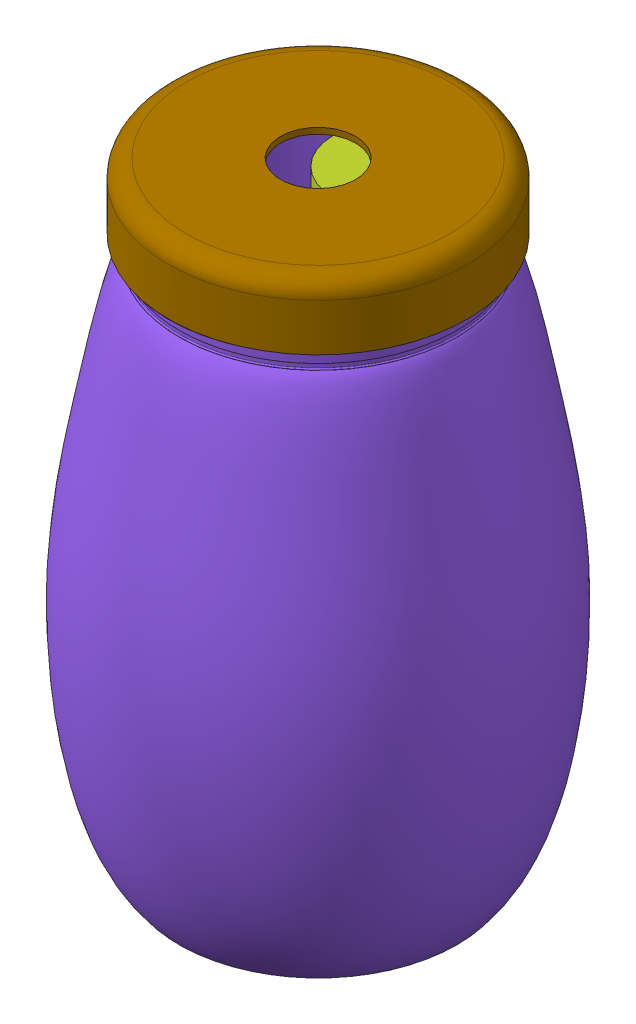
SolidWorks assembly FinalAssem, configuration Default. Lengths in mm.
Overall size (70.17 110.51 70.61).
12 component instances, 9 part files, 18 mates.
Components (placement in the parent):
- final.step-1: final.step [Default] at (-156.8104 99.0685 -1.6) size (33 52.2 1.6)
  - _autosave-final PCB.step-1: _autosave-final PCB.step [Default] at origin size (33 52.2 1.6)
- 30mm Button.STEP-1: 30mm Button.STEP [Default] at (-127.7013 -1.3511 -1.5934) x (-1 0 0) z (0 0 1) size (33.02 41.99 35.3)
  - top_cap.STEP-1: top_cap.STEP [Default] at (-11.8549 16.7258 1.5934) size (26.67 15.14 24.94)
  - base.STEP-1: base.STEP [Default] at (-11.8549 15.7525 1.5934) size (33.02 22.1 35.3)
  - microswitch.STEP-1: microswitch.STEP [Default] at (-11.8549 -8.6795 1.5934) x (1 0 0) z (0 1 0) size (15.01 12.06 29.85)
- JSTconnect.step-1: JSTconnect.step [Default] at (-104.0259 51.1464 0) x (0 1 0) z (1 0 0) size (7.9 5.6 8.6)
- OnOffSwitch.stp-1: OnOffSwitch.stp [Default] at (-113.8259 61.3214 0) x (1 0 0) z (0 -1 0) size (7.7 1.9 5)
  - PCM12SMTR_PART1.stp-1: PCM12SMTR_PART1.stp [Default] at origin size (7.7 1.9 5)
- battery-1: battery [Default] at (-115.8464 79.3964 -11.5) x (1 0 0) z (0 0 -1) size (18 69 18)
- CasingBottom-1: CasingBottom [Default] at (-115.8464 -17.1036 0) size (69.87 100.84 69.87)
- CasingTop-1: CasingTop [Default] at (-115.8464 75.3964 0) x (0.868987 0 -0.494835) z (0.494835 0 0.868987) size (50.92 11.84 52.26)
Mates (geometry in assembly coordinates):
- Concentric1: concentric aligned: cylinder of final.step-1/_autosave-final PCB.step-1 through (-115.3259 61.3214 -2.4) axis (0 0 1) radius 0.45; cylinder of OnOffSwitch.stp-1/PCM12SMTR_PART1.stp-1 through (-115.3259 61.3214 0) axis (0 0 1) radius 0.4
- Coincident2: coincident anti-aligned: plane of final.step-1/_autosave-final PCB.step-1 through (-120.5259 36.9964 0) normal (0 0 1); plane of OnOffSwitch.stp-1/PCM12SMTR_PART1.stp-1 through (-113.8259 61.3214 0) normal (0 0 -1)
- Concentric2: concentric aligned: cylinder of final.step-1/_autosave-final PCB.step-1 through (-112.3259 61.3214 -2.4) axis (0 0 1) radius 0.45; cylinder of OnOffSwitch.stp-1/PCM12SMTR_PART1.stp-1 through (-112.3259 61.3214 0) axis (0 0 1) radius 0.4
- Coincident12: coincident anti-aligned: plane of final.step-1/_autosave-final PCB.step-1 through (-120.5259 36.9964 0) normal (0 0 1); plane of JSTconnect.step-1 through (-111.6259 47.1964 0) normal (0 0 -1)
- Coincident13: coincident aligned: plane of final.step-1/_autosave-final PCB.step-1 through (-104.0259 63.0964 -1.6) normal (1 0 0); plane of JSTconnect.step-1 through (-104.0259 55.0964 5.5) normal (1 0 0)
- Parallel12: parallel anti-aligned: plane of final.step-1/_autosave-final PCB.step-1 through (-104.0259 10.8964 -1.6) normal (0 -1 0); plane of 30mm Button.STEP-1/base.STEP-1 through (-130.5784 1.9944 0) normal (0 1 0)
- Concentric3: concentric aligned: cylinder of 30mm Button.STEP-1/base.STEP-1 through (-115.8464 -20.1036 0) axis (0 -1 0) radius 14.732; cylinder of CasingBottom-1 through (-115.8464 -17.1036 0) axis (0 -1 0) radius 23.5
- Coincident17: coincident anti-aligned: plane of 30mm Button.STEP-1/base.STEP-1 through (-130.5784 -17.1036 0) normal (0 1 0); plane of CasingBottom-1 through (-115.8464 -17.1036 0) normal (0 -1 0)
- Parallel13: parallel aligned: plane of 30mm Button.STEP-1/microswitch.STEP-1 through (-109.3694 -5.3716 6.0325) normal (0 0 1); plane of CasingBottom-1 through (-115.8464 -17.1036 0) normal (0 0 1)
- Distance1: distance = 8 mm aligned: plane of JSTconnect.step-1 through (-104.0259 55.0964 5.5) normal (0 1 0); plane of final.step-1/_autosave-final PCB.step-1 through (-137.0259 63.0964 -1.6) normal (0 1 0)
- Coincident18: coincident anti-aligned: plane of final.step-1/_autosave-final PCB.step-1 through (-104.0259 10.8964 -1.6) normal (0 -1 0); plane of CasingBottom-1 through (-115.8464 10.8964 0) normal (0 1 0)
- Coincident19: coincident anti-aligned: plane of final.step-1/_autosave-final PCB.step-1 through (-120.5259 36.9964 0) normal (0 0 1); plane of CasingBottom-1 through (-115.8464 15.8964 0) normal (0 0 -1)
- Coincident20: coincident: plane of final.step-1/_autosave-final PCB.step-1 through (-104.0259 63.0964 -1.6) normal (1 0 0); line of CasingBottom-1 through (-104.0259 15.8964 0) axis (0 0 -1)
- Concentric4: concentric anti-aligned: circle of battery-1; circle of CasingBottom-1
- Coincident21: coincident anti-aligned: plane of battery-1 through (-115.8464 10.3964 -11.5) normal (0 -1 0); plane of CasingBottom-1 through (-115.8464 10.3964 -11.5) normal (0 1 0)
- Concentric5: concentric anti-aligned: cylinder of CasingBottom-1 through (-115.8464 -17.1036 0) axis (0 -1 0) radius 22; circle of CasingTop-1
- Coincident23: coincident: plane of CasingBottom-1 through (-115.8464 82.8964 0) normal (0 1 0); point of CasingTop-1
- Coincident24: coincident aligned: plane of CasingBottom-1 through (-115.8464 -17.1036 0) normal (0 0 1)
